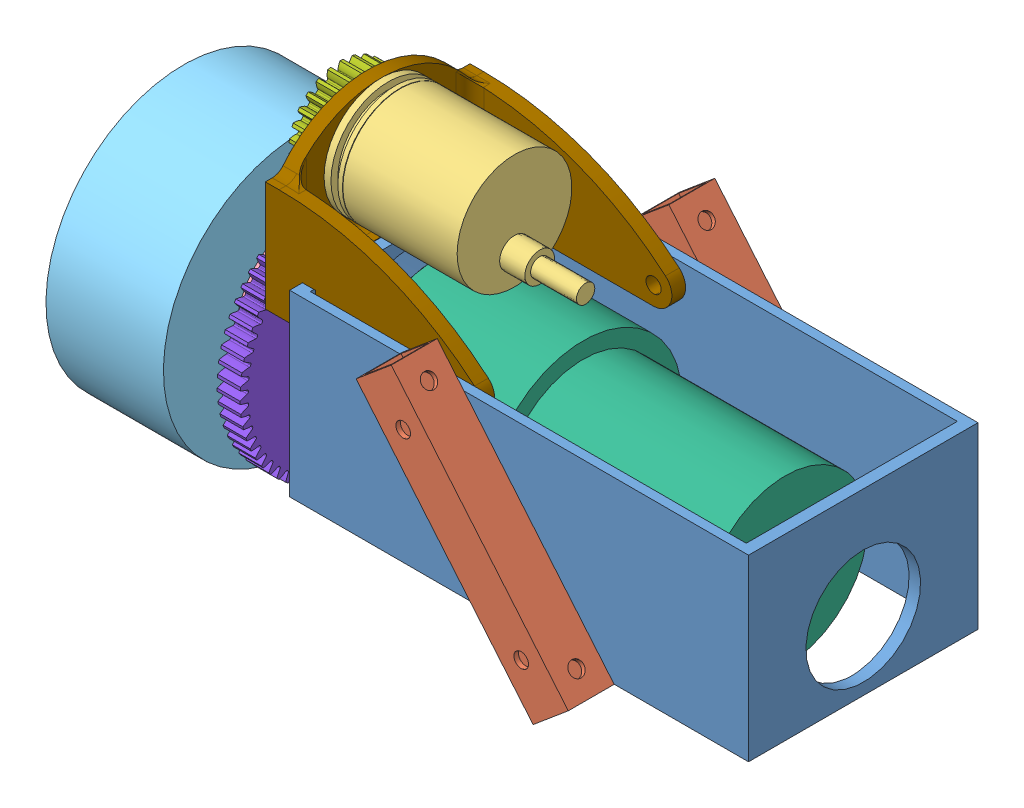
SolidWorks assembly 脚ユニット, configuration ﾃﾞﾌｫﾙﾄ. Lengths in mm.
Overall size (148.1 79.92 70.5).
11 component instances, 10 part files, 29 mates.
Components (placement in the parent):
- モータエンコーダ取り付け角柱-1: モータエンコーダ取り付け角柱 [ﾃﾞﾌｫﾙﾄ] at (20.22 50.0169 59.6568) x (1 0 0) z (0 -1 0) size (100 50 39)
- 土台と脚取り付け角柱-1: 土台と脚取り付け角柱 [ﾃﾞﾌｫﾙﾄ] at (18.0757 50.5169 29.4068) x (0.766044 0.642788 0) z (0.642788 -0.766044 0) size (10 10 60)
- 土台と脚取り付け角柱-2: 土台と脚取り付け角柱 [ﾃﾞﾌｫﾙﾄ] at (18.0757 50.5169 89.9068) x (0.766044 0.642788 0) z (0.642788 -0.766044 0) size (10 10 60)
- E6A2_CW3C-1: E6A2_CW3C [ﾃﾞﾌｫﾙﾄ] at (-34.78 82.1169 68.6568) x (0 0 1) z (-1 0 0) size (25 25 56.5)
- オムニ用ハブ-1: オムニ用ハブ [ﾃﾞﾌｫﾙﾄ] at (-52.28 45.5169 59.6568) x (1 0 0) z (0 -0.475862 0.87952) size (16 28 28)
- オムニホイール-1: オムニホイール [ﾃﾞﾌｫﾙﾄ] at (-52.28 45.5169 59.6568) x (-1 0 0) z (0 -0.027652 -0.999618) size (25.6 60 60)
- モータ_ツカサ電工-1: モータ_ツカサ電工 [ﾃﾞﾌｫﾙﾄ] at (9.22 45.5169 59.6568) x (0 0 -1) z (-1 0 0) size (43 43 101)
- エンコーダ歯車-1: エンコーダ歯車 [デフォルト] at (-38.78 82.1169 59.6568) x (0 0.046374 -0.998924) z (1 0 0) size (22.4 22.38 5)
- モータ伝達歯車-1: モータ伝達歯車 [アクリル切り出し] at (-41.28 45.5169 59.6568) x (0 0.999618 -0.027652) z (-1 0 0) size (53.59 53.59 5)
- エンコーダ取付3D部品-1: エンコーダ取付3D部品 [ﾃﾞﾌｫﾙﾄ] at (-37.78 45.7169 59.6568) x (0 0 1) z (-1 0 0) size (44.6 34 47)
- モータ取り付けアクリル板-1: モータ取り付けアクリル板 [ﾃﾞﾌｫﾙﾄ] at (-27.28 45.5169 59.6568) x (0 -0.866025 -0.5) z (1 0 0) size (43 43 5)
Mates (geometry in assembly coordinates):
- 同心円1: concentric: circle of モータエンコーダ取り付け角柱-1; circle of 土台と脚取り付け角柱-1
- 同心円2: concentric: circle of モータエンコーダ取り付け角柱-1; circle of 土台と脚取り付け角柱-1
- 同心円3: concentric: circle of モータエンコーダ取り付け角柱-1; circle of 土台と脚取り付け角柱-2
- 同心円4: concentric: circle of モータエンコーダ取り付け角柱-1; circle of 土台と脚取り付け角柱-2
- 距離3: distance = 0.25 mm: plane of モータエンコーダ取り付け角柱-1 through (-29.78 30.5169 34.6568) normal (0 0 -1); plane of 土台と脚取り付け角柱-1 through (33.5291 24.3216 34.4068) normal (0 0 1)
- 距離4: distance = 0.25 mm: plane of モータエンコーダ取り付け角柱-1 through (-29.78 30.5169 84.6568) normal (0 0 1); plane of 土台と脚取り付け角柱-2 through (33.5291 24.3216 84.9068) normal (0 0 -1)
- 同心円9: concentric: circle of オムニ用ハブ-1; circle of オムニホイール-1
- 同心円10: concentric: circle of オムニホイール-1; circle of オムニ用ハブ-1
- 同心円11: concentric: circle of モータエンコーダ取り付け角柱-1; circle of モータ_ツカサ電工-1
- 同心円12: concentric: circle of モータエンコーダ取り付け角柱-1; circle of モータ_ツカサ電工-1
- 距離6: distance = 5 mm: plane of モータエンコーダ取り付け角柱-1 through (-27.28 30.5169 36.6568) normal (1 0 0); plane of モータ_ツカサ電工-1 through (-22.28 45.5169 59.6568) normal (-1 0 0)
- 同心円13: concentric: circle of オムニ用ハブ-1; cylinder of モータ_ツカサ電工-1 through (-47.78 45.5169 59.6568) axis (1 0 0) radius 4
- 同心円14: concentric: cylinder of E6A2_CW3C-1 through (-18.3511 82.1169 59.6568) axis (1 0 0) radius 2; circle of エンコーダ歯車-1
- 同心円15: concentric: cylinder of モータ_ツカサ電工-1 through (-47.78 45.5169 59.6568) axis (1 0 0) radius 4; cylinder of モータ伝達歯車-1 through (-38.78 45.5169 59.6568) axis (-1 0 0) radius 7.525
- 同心円16: concentric: circle of オムニ用ハブ-1; circle of モータ伝達歯車-1
- 一致9: coincident: plane of オムニ用ハブ-1 through (-52.28 45.5169 59.6568) normal (-1 0 0); plane of オムニホイール-1 through (-52.28 45.5169 59.6568) normal (1 0 0)
- 一致10: coincident: plane of エンコーダ歯車-1 through (-43.78 82.1169 59.6568) normal (-1 0 0); plane of モータ伝達歯車-1 through (-43.78 45.5169 59.6568) normal (-1 0 0)
- 距離5: distance = 21 mm: plane of オムニ用ハブ-1 through (-48.28 45.5169 59.6568) normal (1 0 0); plane of モータ_ツカサ電工-1 through (-27.28 45.5169 59.6568) normal (-1 0 0)
- 一致12: coincident: plane of E6A2_CW3C-1 through (-38.78 82.1169 59.6568) normal (-1 0 0); plane of エンコーダ歯車-1 through (-38.78 82.1169 59.6568) normal (1 0 0)
- 同心円17: concentric: circle of モータエンコーダ取り付け角柱-1; circle of エンコーダ取付3D部品-1
- 平行1: parallel: line of モータエンコーダ取り付け角柱-1 through (-29.78 69.5169 84.6568) axis (0 0 -1); line of エンコーダ取付3D部品-1 through (-29.78 60.6169 37.3568) axis (0 0 1)
- 一致13: coincident: plane of モータエンコーダ取り付け角柱-1 through (-29.78 30.5169 34.6568) normal (-1 0 0); plane of エンコーダ取付3D部品-1 through (-29.78 45.7169 59.6568) normal (1 0 0)
- 同心円18: concentric: circle of E6A2_CW3C-1; circle of エンコーダ取付3D部品-1
- 同心円19: concentric: circle of E6A2_CW3C-1; circle of エンコーダ取付3D部品-1
- 一致14: coincident: plane of E6A2_CW3C-1 through (-34.78 82.1169 59.6568) normal (-1 0 0); plane of エンコーダ取付3D部品-1 through (-34.78 45.7169 59.6568) normal (1 0 0)
- ｷﾞｱ合致1: gear = 5 : 2 mm: circle of エンコーダ歯車-1; circle of モータ伝達歯車-1
- 同心円22: concentric: cylinder of モータ_ツカサ電工-1 through (-22.28 45.5169 59.6568) axis (1 0 0) radius 21.5; cylinder of モータ取り付けアクリル板-1 through (-22.28 45.5169 59.6568) axis (-1 0 0) radius 21.5
- 同心円25: concentric: circle of モータ_ツカサ電工-1; circle of モータ取り付けアクリル板-1
- 一致15: coincident: plane of モータ_ツカサ電工-1 through (-22.28 45.5169 59.6568) normal (-1 0 0); plane of モータ取り付けアクリル板-1 through (-22.28 45.5169 59.6568) normal (1 0 0)
